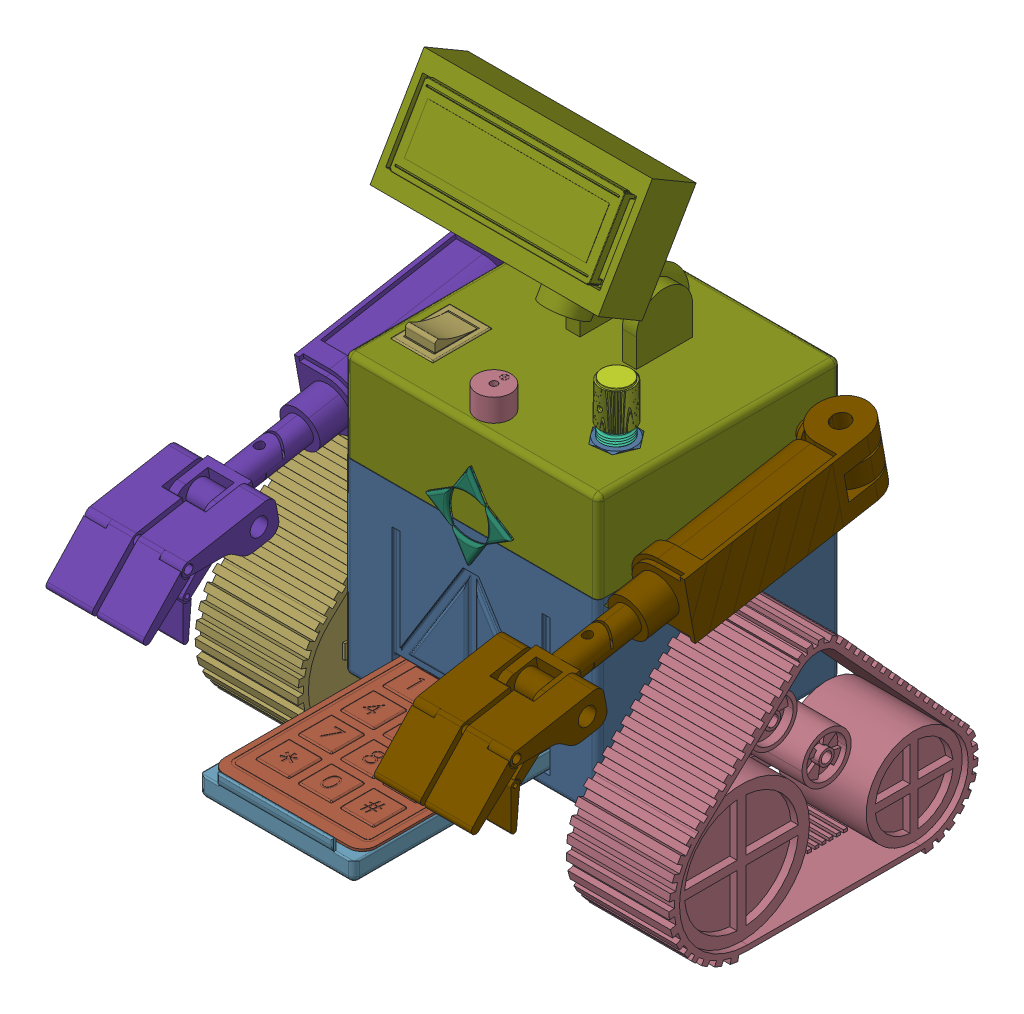
SolidWorks assembly Full Body with arms and wheels, configuration Default. Lengths in mm.
Overall size (168.14 212.39 174.48).
196 component instances, 67 part files, 27 mates.
Components (placement in the parent):
- Clock PCB.step-1: Clock PCB.step [Default] at (-3.837 -6.133 58.5856) size (81.95 80 25.5)
  - Board.step-1: Board.step [Default] at origin size (80 80 0.41)
    - Open CASCADE STEP translator 6.8 1.1.1.step-1: Open CASCADE STEP translator 6.8 1.1.1.step [Default] at (0 0 -0.4115) size (80 80 0.41)
  - XTAL1.step-1: XTAL1.step [Default] at origin size (11.36 4.66 3.61)
    - 6606830048.step-1: 6606830048.step [Default] at (28.0499 41.0499 0) size (11.36 4.66 1.01)
      - Extruded.step-1: Extruded.step [Default] at origin size (11.36 4.66 1.01)
    - 6606829968.step-1: 6606829968.step [Default] at (28.0499 41.0501 1) size (10.05 3.71 2.61)
      - Extruded-0.step-1: Extruded-0.step [Default] at origin size (10.05 3.71 2.61)
  - U2.step-1: U2.step [Default] at origin size (10.5 4.7 16.2)
    - 6606829888.step-1: 6606829888.step [Default] at (7.95 27.55 13.05) size (10.4 1.3 6.65)
      - Extruded-1.step-1: Extruded-1.step [Default] at origin size (10.4 1.3 6.65)
    - 6606829728.step-1: 6606829728.step [Default] at (7.95 25.9 3.5) size (10.5 4.7 9.55)
      - Extruded-2.step-1: Extruded-2.step [Default] at origin size (10.5 4.7 9.55)
  - U1.step-1: U1.step [Default] at origin size (63.7 16.03 14.45)
    - User_Library-ZIF-Socket-28-pin.step-1: User_Library-ZIF-Socket-28-pin.step [Default] at (43.5 28.05 0) x (1 0 0) z (0 0 1) size (63.7 16.03 14.45)
      - Contacts.step-1: Contacts.step [Default] at origin size (34.37 11.24 1.5)
      - Pins001.step-1: Pins001.step [Default] at origin size (33.87 8.47 3)
      - Screw002.step-1: Screw002.step [Default] at origin size (2.8 2.8 2)
      - Bottom-Shape.step-1: Bottom-Shape.step [Default] at origin size (50.4 15.02 8.11)
      - Lever-Tip.step-1: Lever-Tip.step [Default] at origin size (7 4.8 4.8)
      - Top-Shape.step-1: Top-Shape.step [Default] at origin size (50.4 15.02 3.8)
      - Push-Bar.step-1: Push-Bar.step [Default] at origin size (3.85 15.02 3.7)
      - Lever-Bar.step-1: Lever-Bar.step [Default] at origin size (19.2 11.43 1.62)
      - Screw001.step-1: Screw001.step [Default] at origin size (2.8 2.8 2)
  - Q1.step-1: Q1.step [Default] at origin size (3.05 4.08 12.8)
    - BC547-B.step-1: BC547-B.step [Default] at (72 53.1536 7) x (0 1 0) z (0 0 -1) size (4.08 3.05 12.8)
  - P3.step-1: P3.step [Default] at origin size (2.54 10.16 11.54)
    - 61300411121.step-1: 61300411121.step [Default] at (76.2999 22.6001 1.3) x (0 1 0) z (1 0 0) size (10.16 11.54 2.54)
      - 6130xx11121_PIN.step-1: 6130xx11121_PIN.step [Default] at (-3.81 1.5 0) x (1 0 0) z (0 -1 0) size (0.64 0.64 11.54)
      - 6130xx11121_PIN.step-2: 6130xx11121_PIN.step [Default] at (-1.27 1.5 0) x (1 0 0) z (0 -1 0) size (0.64 0.64 11.54)
      - 6130xx11121_PIN.step-3: 6130xx11121_PIN.step [Default] at (1.27 1.5 0) x (1 0 0) z (0 -1 0) size (0.64 0.64 11.54)
      - 6130xx11121_PIN.step-4: 6130xx11121_PIN.step [Default] at (3.81 1.5 0) x (1 0 0) z (0 -1 0) size (0.64 0.64 11.54)
      - 61300411121-3.step-1: 61300411121-3.step [Default] at origin size (10.16 2.54 2.54)
  - P2.step-1: P2.step [Default] at origin size (17.78 2.54 11.54)
    - 61300711121.step-1: 61300711121.step [Default] at (39.9599 3.8999 1.3) x (-1 0 0) z (0 1 0) size (17.78 11.54 2.54)
      - 6130xx11121_PIN-4.step-1: 6130xx11121_PIN-4.step [Default] at (-7.62 1.5 0) x (1 0 0) z (0 -1 0) size (0.64 0.64 11.54)
      - 6130xx11121_PIN-4.step-2: 6130xx11121_PIN-4.step [Default] at (-5.08 1.5 0) x (1 0 0) z (0 -1 0) size (0.64 0.64 11.54)
      - 6130xx11121_PIN-4.step-3: 6130xx11121_PIN-4.step [Default] at (-2.54 1.5 0) x (1 0 0) z (0 -1 0) size (0.64 0.64 11.54)
      - 6130xx11121_PIN-4.step-4: 6130xx11121_PIN-4.step [Default] at (0 1.5 0) x (1 0 0) z (0 -1 0) size (0.64 0.64 11.54)
      - 6130xx11121_PIN-4.step-5: 6130xx11121_PIN-4.step [Default] at (2.54 1.5 0) x (1 0 0) z (0 -1 0) size (0.64 0.64 11.54)
      - 6130xx11121_PIN-4.step-6: 6130xx11121_PIN-4.step [Default] at (5.08 1.5 0) x (1 0 0) z (0 -1 0) size (0.64 0.64 11.54)
      - 6130xx11121_PIN-4.step-7: 6130xx11121_PIN-4.step [Default] at (7.62 1.5 0) x (1 0 0) z (0 -1 0) size (0.64 0.64 11.54)
      - 61300711121-5.step-1: 61300711121-5.step [Default] at origin size (17.78 2.54 2.54)
  - P1.step-1: P1.step [Default] at origin size (30.48 2.54 11.54)
    - 61301211121.step-1: 61301211121.step [Default] at (41.3799 75.6999 1.3) x (-1 0 0) z (0 1 0) size (30.48 11.54 2.54)
      - 6130xx11121_PIN-6.step-1: 6130xx11121_PIN-6.step [Default] at (-13.97 1.5 0) x (1 0 0) z (0 -1 0) size (0.64 0.64 11.54)
      - 6130xx11121_PIN-6.step-2: 6130xx11121_PIN-6.step [Default] at (-11.43 1.5 0) x (1 0 0) z (0 -1 0) size (0.64 0.64 11.54)
      - 6130xx11121_PIN-6.step-3: 6130xx11121_PIN-6.step [Default] at (-8.89 1.5 0) x (1 0 0) z (0 -1 0) size (0.64 0.64 11.54)
      - 6130xx11121_PIN-6.step-4: 6130xx11121_PIN-6.step [Default] at (-6.35 1.5 0) x (1 0 0) z (0 -1 0) size (0.64 0.64 11.54)
      - 6130xx11121_PIN-6.step-5: 6130xx11121_PIN-6.step [Default] at (-3.81 1.5 0) x (1 0 0) z (0 -1 0) size (0.64 0.64 11.54)
      - 6130xx11121_PIN-6.step-6: 6130xx11121_PIN-6.step [Default] at (-1.27 1.5 0) x (1 0 0) z (0 -1 0) size (0.64 0.64 11.54)
      - 6130xx11121_PIN-6.step-7: 6130xx11121_PIN-6.step [Default] at (1.27 1.5 0) x (1 0 0) z (0 -1 0) size (0.64 0.64 11.54)
      - 6130xx11121_PIN-6.step-8: 6130xx11121_PIN-6.step [Default] at (3.81 1.5 0) x (1 0 0) z (0 -1 0) size (0.64 0.64 11.54)
      - 6130xx11121_PIN-6.step-9: 6130xx11121_PIN-6.step [Default] at (6.35 1.5 0) x (1 0 0) z (0 -1 0) size (0.64 0.64 11.54)
      - 6130xx11121_PIN-6.step-10: 6130xx11121_PIN-6.step [Default] at (8.89 1.5 0) x (1 0 0) z (0 -1 0) size (0.64 0.64 11.54)
      - 6130xx11121_PIN-6.step-11: 6130xx11121_PIN-6.step [Default] at (11.43 1.5 0) x (1 0 0) z (0 -1 0) size (0.64 0.64 11.54)
      - 6130xx11121_PIN-6.step-12: 6130xx11121_PIN-6.step [Default] at (13.97 1.5 0) x (1 0 0) z (0 -1 0) size (0.64 0.64 11.54)
      - 61301211121-7.step-1: 61301211121-7.step [Default] at origin size (30.48 2.54 2.54)
  - KEY5.step-1: KEY5.step [Default] at origin size (7.8 5.99 8.11)
    - Switch_TE_1825910-2_eec.step-1: Switch_TE_1825910-2_eec.step [Default] at (68.1 13.85 0) size (7.8 5.99 8.11)
      - Body.step-1: Body.step [Default] at (0 0 4.3) x (0 -1 0) z (0 0 1) size (5.99 5.99 3.9)
      - button.step-1: button.step [Default] at (0 0 4.3) x (0 -1 0) z (0 0 1) size (3.51 3.51 1.1)
      - cover.step-1: cover.step [Default] at (0 0 4.3) x (0 -1 0) z (0 0 1) size (5.99 5.99 0.1)
      - leads.step-1: leads.step [Default] at (0 0 4.3) x (0 -1 0) z (0 0 1) size (5.21 7.8 4.81)
      - circle.step-1: circle.step [Default] at (-2.6803 2.6863 3.6) size (0.4 0.4 0)
      - TE_Connectivity.step-1: TE_Connectivity.step [Default] at (-0.1925 -2.4218 3.6) size (2.27 0.85 0.01)
  - KEY4.step-1: KEY4.step [Default] at origin size (7.8 5.99 8.11)
    - Switch_TE_1825910-2_eec.step-1: Switch_TE_1825910-2_eec.step [Default] at (50 55 0) size (7.8 5.99 8.11)
      - Body.step-1: Body.step [Default] at (0 0 4.3) x (0 -1 0) z (0 0 1) size (5.99 5.99 3.9)
      - button.step-1: button.step [Default] at (0 0 4.3) x (0 -1 0) z (0 0 1) size (3.51 3.51 1.1)
      - cover.step-1: cover.step [Default] at (0 0 4.3) x (0 -1 0) z (0 0 1) size (5.99 5.99 0.1)
      - leads.step-1: leads.step [Default] at (0 0 4.3) x (0 -1 0) z (0 0 1) size (5.21 7.8 4.81)
      - circle.step-1: circle.step [Default] at (-2.6803 2.6863 3.6) size (0.4 0.4 0)
      - TE_Connectivity.step-1: TE_Connectivity.step [Default] at (-0.1925 -2.4218 3.6) size (2.27 0.85 0.01)
  - KEY3.step-1: KEY3.step [Default] at origin size (7.8 5.99 8.11)
    - Switch_TE_1825910-2_eec.step-1: Switch_TE_1825910-2_eec.step [Default] at (30 55 0) size (7.8 5.99 8.11)
      - Body.step-1: Body.step [Default] at (0 0 4.3) x (0 -1 0) z (0 0 1) size (5.99 5.99 3.9)
      - button.step-1: button.step [Default] at (0 0 4.3) x (0 -1 0) z (0 0 1) size (3.51 3.51 1.1)
      - cover.step-1: cover.step [Default] at (0 0 4.3) x (0 -1 0) z (0 0 1) size (5.99 5.99 0.1)
      - leads.step-1: leads.step [Default] at (0 0 4.3) x (0 -1 0) z (0 0 1) size (5.21 7.8 4.81)
      - circle.step-1: circle.step [Default] at (-2.6803 2.6863 3.6) size (0.4 0.4 0)
      - TE_Connectivity.step-1: TE_Connectivity.step [Default] at (-0.1925 -2.4218 3.6) size (2.27 0.85 0.01)
  - KEY2.step-1: KEY2.step [Default] at origin size (7.8 5.99 8.11)
    - Switch_TE_1825910-2_eec.step-1: Switch_TE_1825910-2_eec.step [Default] at (40 45 0) size (7.8 5.99 8.11)
      - Body.step-1: Body.step [Default] at (0 0 4.3) x (0 -1 0) z (0 0 1) size (5.99 5.99 3.9)
      - button.step-1: button.step [Default] at (0 0 4.3) x (0 -1 0) z (0 0 1) size (3.51 3.51 1.1)
      - cover.step-1: cover.step [Default] at (0 0 4.3) x (0 -1 0) z (0 0 1) size (5.99 5.99 0.1)
      - leads.step-1: leads.step [Default] at (0 0 4.3) x (0 -1 0) z (0 0 1) size (5.21 7.8 4.81)
      - circle.step-1: circle.step [Default] at (-2.6803 2.6863 3.6) size (0.4 0.4 0)
      - TE_Connectivity.step-1: TE_Connectivity.step [Default] at (-0.1925 -2.4218 3.6) size (2.27 0.85 0.01)
  - KEY1.step-1: KEY1.step [Default] at origin size (7.8 5.99 8.11)
    - Switch_TE_1825910-2_eec.step-1: Switch_TE_1825910-2_eec.step [Default] at (40 65 0) size (7.8 5.99 8.11)
      - Body.step-1: Body.step [Default] at (0 0 4.3) x (0 -1 0) z (0 0 1) size (5.99 5.99 3.9)
      - button.step-1: button.step [Default] at (0 0 4.3) x (0 -1 0) z (0 0 1) size (3.51 3.51 1.1)
      - cover.step-1: cover.step [Default] at (0 0 4.3) x (0 -1 0) z (0 0 1) size (5.99 5.99 0.1)
      - leads.step-1: leads.step [Default] at (0 0 4.3) x (0 -1 0) z (0 0 1) size (5.21 7.8 4.81)
      - circle.step-1: circle.step [Default] at (-2.6803 2.6863 3.6) size (0.4 0.4 0)
      - TE_Connectivity.step-1: TE_Connectivity.step [Default] at (-0.1925 -2.4218 3.6) size (2.27 0.85 0.01)
  - JST2.step-1: JST2.step [Default] at origin size (4.7 6 10.05)
    - Conn_TE_Connectivity_440054-2_eec.step-1: Conn_TE_Connectivity_440054-2_eec.step [Default] at (72.85 68.85 0) x (0 -1 0) z (0 0 1) size (6 4.7 10.05)
      - 1.step-1: 1.step [Default] at (0 -0.6 6.05) size (2.5 2.35 8.8)
      - 2.step-1: 2.step [Default] at (0 -0.6 6.05) size (0.9 0.1 1.08)
      - 3.step-1: 3.step [Default] at (0 -0.6 6.05) size (6 4.7 6.35)
      - TE_connectivity_Logo_1_(2).step-1: TE_connectivity_Logo_1_(2).step [Default] at (2.901 6.9182 0.6322) x (0 -1 0) z (1 0 0) size (1.49 0.53 0.1)
  - JST1.step-1: JST1.step [Default] at origin size (6 4.7 10.05)
    - Conn_TE_Connectivity_440054-2_eec.step-1: Conn_TE_Connectivity_440054-2_eec.step [Default] at (10.55 4.25 0) x (-1 0 0) z (0 0 1) size (6 4.7 10.05)
      - 1.step-1: 1.step [Default] at (0 -0.6 6.05) size (2.5 2.35 8.8)
      - 2.step-1: 2.step [Default] at (0 -0.6 6.05) size (0.9 0.1 1.08)
      - 3.step-1: 3.step [Default] at (0 -0.6 6.05) size (6 4.7 6.35)
      - TE_connectivity_Logo_1_(2).step-1: TE_connectivity_Logo_1_(2).step [Default] at (2.901 6.9182 0.6322) x (0 -1 0) z (1 0 0) size (1.49 0.53 0.1)
  - JST3.step-1: JST3.step [Default] at origin size (7.9 4.5 9.4)
    - 6606829248.step-1: 6606829248.step [Default] at (11.9 70.55 -3.4) size (0.5 0.5 8.45)
      - Extruded-8.step-1: Extruded-8.step [Default] at origin size (0.5 0.5 8.45)
    - 6606829248.step-2: 6606829248.step [Default] at (7.9 70.55 -3.4) size (0.5 0.5 8.45)
      - Extruded-8.step-1: Extruded-8.step [Default] at origin size (0.5 0.5 8.45)
    - 6606829248.step-3: 6606829248.step [Default] at (9.9 70.55 -3.4) size (0.5 0.5 8.45)
      - Extruded-8.step-1: Extruded-8.step [Default] at origin size (0.5 0.5 8.45)
    - 6606828928.step-1: 6606828928.step [Default] at (9.9 70.2 0) size (6.6 4.1 1.75)
      - Extruded-9.step-1: Extruded-9.step [Default] at origin size (6.6 4.1 1.75)
    - 6606828768.step-1: 6606828768.step [Default] at (9.9 68.875 0) size (7.9 2.25 6)
      - Extruded-10.step-1: Extruded-10.step [Default] at origin size (7.9 2.25 6)
    - 6606828608.step-1: 6606828608.step [Default] at (7.525 71.525 0) size (3.15 1.45 6)
      - Extruded-11.step-1: Extruded-11.step [Default] at origin size (3.15 1.45 6)
    - 6606828448.step-1: 6606828448.step [Default] at (6.275 70.4 0) size (0.65 0.8 4.1)
      - Extruded-12.step-1: Extruded-12.step [Default] at origin size (0.65 0.8 4.1)
    - 6606828448.step-2: 6606828448.step [Default] at (13.525 70.4 0) size (0.65 0.8 4.1)
      - Extruded-12.step-1: Extruded-12.step [Default] at origin size (0.65 0.8 4.1)
    - 6606828208.step-1: 6606828208.step [Default] at (12.275 71.525 0) size (3.15 1.45 6)
      - Extruded-13.step-1: Extruded-13.step [Default] at origin size (3.15 1.45 6)
  - C6.step-1: C6.step [Default] at origin size (8 8 14.5)
    - Aluminum_electrolytic_capacitor_radial_D8_H11.5_PinD0.6_Pitch3.5_nominal_black.step-1: Aluminum_electrolytic_capacitor_radial_D8_H11.5_PinD0.6_Pitch3.5_nominal_black.step [Default] at (64.35 73.55 0) x (-1 0 0) z (0 0 1) size (1.1 2.07 11.1)
    - Aluminum_electrolytic_capacitor_radial_D8_H11.5_PinD0.6_Pitch3.5_nominal_black-14.step-1: Aluminum_electrolytic_capacitor_radial_D8_H11.5_PinD0.6_Pitch3.5_nominal_black-14.step [Default] at (64.35 73.55 0) x (-1 0 0) z (0 0 1) size (7.86 8 11.1)
    - Aluminum_electrolytic_capacitor_radial_D8_H11.5_PinD0.6_Pitch3.5_nominal_black-15.step-1: Aluminum_electrolytic_capacitor_radial_D8_H11.5_PinD0.6_Pitch3.5_nominal_black-15.step [Default] at (64.35 73.55 0) x (-1 0 0) z (0 0 1) size (7.8 7.8 10.9)
    - Aluminum_electrolytic_capacitor_radial_D8_H11.5_PinD0.6_Pitch3.5_nominal_black-16.step-1: Aluminum_electrolytic_capacitor_radial_D8_H11.5_PinD0.6_Pitch3.5_nominal_black-16.step [Default] at (64.35 73.55 0) x (-1 0 0) z (0 0 1) size (7.4 7.4 1.6)
    - Aluminum_electrolytic_capacitor_radial_D8_H11.5_PinD0.6_Pitch3.5_nominal_black-17.step-1: Aluminum_electrolytic_capacitor_radial_D8_H11.5_PinD0.6_Pitch3.5_nominal_black-17.step [Default] at (64.35 73.55 0) x (-1 0 0) z (0 0 1) size (4.1 0.6 3)
  - C5.step-1: C5.step [Default] at origin size (8 8 14.5)
    - Aluminum_electrolytic_capacitor_radial_D8_H11.5_PinD0.6_Pitch3.5_nominal_black.step-1: Aluminum_electrolytic_capacitor_radial_D8_H11.5_PinD0.6_Pitch3.5_nominal_black.step [Default] at (65.05 5.25 0) size (1.1 2.07 11.1)
    - Aluminum_electrolytic_capacitor_radial_D8_H11.5_PinD0.6_Pitch3.5_nominal_black-14.step-1: Aluminum_electrolytic_capacitor_radial_D8_H11.5_PinD0.6_Pitch3.5_nominal_black-14.step [Default] at (65.05 5.25 0) size (7.86 8 11.1)
    - Aluminum_electrolytic_capacitor_radial_D8_H11.5_PinD0.6_Pitch3.5_nominal_black-15.step-1: Aluminum_electrolytic_capacitor_radial_D8_H11.5_PinD0.6_Pitch3.5_nominal_black-15.step [Default] at (65.05 5.25 0) size (7.8 7.8 10.9)
    - Aluminum_electrolytic_capacitor_radial_D8_H11.5_PinD0.6_Pitch3.5_nominal_black-16.step-1: Aluminum_electrolytic_capacitor_radial_D8_H11.5_PinD0.6_Pitch3.5_nominal_black-16.step [Default] at (65.05 5.25 0) size (7.4 7.4 1.6)
    - Aluminum_electrolytic_capacitor_radial_D8_H11.5_PinD0.6_Pitch3.5_nominal_black-17.step-1: Aluminum_electrolytic_capacitor_radial_D8_H11.5_PinD0.6_Pitch3.5_nominal_black-17.step [Default] at (65.05 5.25 0) size (4.1 0.6 3)
  - C4.step-1: C4.step [Default] at origin size (5.99 5.99 8.89)
    - Cap_Murata_RCE5C2A3R0C0K1H03B_eec.step-1: Cap_Murata_RCE5C2A3R0C0K1H03B_eec.step [Default] at (13.7 39.4 0) x (1 0 0) z (0 0 1) size (5.99 5.99 8.89)
      - Body.step-1: Body.step [Default] at origin size (5.99 5.99 3.9)
      - leads-18.step-1: leads-18.step [Default] at origin size (5.5 0.5 6.65)
      - logo.step-1: logo.step [Default] at (0 -1.25 8.5) x (1 0 0) z (0 -1 0) size (1.98 0.46 0.01)
  - C3.step-1: C3.step [Default] at origin size (5.99 5.99 8.89)
    - Cap_Murata_RCE5C2A3R0C0K1H03B_eec.step-1: Cap_Murata_RCE5C2A3R0C0K1H03B_eec.step [Default] at (13.65 43.7 0) x (1 0 0) z (0 0 1) size (5.99 5.99 8.89)
      - Body.step-1: Body.step [Default] at origin size (5.99 5.99 3.9)
      - leads-18.step-1: leads-18.step [Default] at origin size (5.5 0.5 6.65)
      - logo.step-1: logo.step [Default] at (0 -1.25 8.5) x (1 0 0) z (0 -1 0) size (1.98 0.46 0.01)
  - C2.step-1: C2.step [Default] at origin size (8 8 14.5)
    - Aluminum_electrolytic_capacitor_radial_D8_H11.5_PinD0.6_Pitch3.5_nominal_black.step-1: Aluminum_electrolytic_capacitor_radial_D8_H11.5_PinD0.6_Pitch3.5_nominal_black.step [Default] at (17.55 14.1 0) size (1.1 2.07 11.1)
    - Aluminum_electrolytic_capacitor_radial_D8_H11.5_PinD0.6_Pitch3.5_nominal_black-14.step-1: Aluminum_electrolytic_capacitor_radial_D8_H11.5_PinD0.6_Pitch3.5_nominal_black-14.step [Default] at (17.55 14.1 0) size (7.86 8 11.1)
    - Aluminum_electrolytic_capacitor_radial_D8_H11.5_PinD0.6_Pitch3.5_nominal_black-15.step-1: Aluminum_electrolytic_capacitor_radial_D8_H11.5_PinD0.6_Pitch3.5_nominal_black-15.step [Default] at (17.55 14.1 0) size (7.8 7.8 10.9)
    - Aluminum_electrolytic_capacitor_radial_D8_H11.5_PinD0.6_Pitch3.5_nominal_black-16.step-1: Aluminum_electrolytic_capacitor_radial_D8_H11.5_PinD0.6_Pitch3.5_nominal_black-16.step [Default] at (17.55 14.1 0) size (7.4 7.4 1.6)
    - Aluminum_electrolytic_capacitor_radial_D8_H11.5_PinD0.6_Pitch3.5_nominal_black-17.step-1: Aluminum_electrolytic_capacitor_radial_D8_H11.5_PinD0.6_Pitch3.5_nominal_black-17.step [Default] at (17.55 14.1 0) size (4.1 0.6 3)
  - C1.step-1: C1.step [Default] at origin size (8 8 14.5)
    - Aluminum_electrolytic_capacitor_radial_D8_H11.5_PinD0.6_Pitch3.5_nominal_black.step-1: Aluminum_electrolytic_capacitor_radial_D8_H11.5_PinD0.6_Pitch3.5_nominal_black.step [Default] at (7.05 14.5 0) size (1.1 2.07 11.1)
    - Aluminum_electrolytic_capacitor_radial_D8_H11.5_PinD0.6_Pitch3.5_nominal_black-14.step-1: Aluminum_electrolytic_capacitor_radial_D8_H11.5_PinD0.6_Pitch3.5_nominal_black-14.step [Default] at (7.05 14.5 0) size (7.86 8 11.1)
    - Aluminum_electrolytic_capacitor_radial_D8_H11.5_PinD0.6_Pitch3.5_nominal_black-15.step-1: Aluminum_electrolytic_capacitor_radial_D8_H11.5_PinD0.6_Pitch3.5_nominal_black-15.step [Default] at (7.05 14.5 0) size (7.8 7.8 10.9)
    - Aluminum_electrolytic_capacitor_radial_D8_H11.5_PinD0.6_Pitch3.5_nominal_black-16.step-1: Aluminum_electrolytic_capacitor_radial_D8_H11.5_PinD0.6_Pitch3.5_nominal_black-16.step [Default] at (7.05 14.5 0) size (7.4 7.4 1.6)
    - Aluminum_electrolytic_capacitor_radial_D8_H11.5_PinD0.6_Pitch3.5_nominal_black-17.step-1: Aluminum_electrolytic_capacitor_radial_D8_H11.5_PinD0.6_Pitch3.5_nominal_black-17.step [Default] at (7.05 14.5 0) size (4.1 0.6 3)
  - Free-Models.step-1: Free-Models.step [Default] at origin size (34.6 9.68 7.3)
    - atmega328p-pu.step-1: atmega328p-pu.step [Default] at (59.217 28 11) x (-1 0 0) z (0 1 0) size (34.6 7.3 9.68)
- Part46^Full Body with arms and wheels-1: Part46^Full Body with arms and wheels [Default] at origin size (90 95.83 86) (virtual)
- Matrix Keypad 12 Key (4X3)-3: Matrix Keypad 12 Key (4X3) [Default] at (35.713 -10.233 128.1202) x (1 0 0) z (0 1 0) size (54 77 1.31)
- wheel 2-2: wheel 2 [Default] at (-18.6112 -22.8736 33.5298) size (56.04 84.58 109.67)
- Mirrorwheel 2-5: Mirrorwheel 2 [Default] at (91.0372 -22.8736 33.5298) x (-1 0 0) z (0 0 -1) size (56.04 84.58 109.67)
- Part4^Full Body with arms and wheels-1: Part4^Full Body with arms and wheels [Default] at (35.713 -10.233 128.1202) x (-1 0 0) z (0 -1 0) size (55 82.09 11) (virtual)
- Part5-1: Part5 [Default] at (0 0 101.5856) size (12.45 10.37 39.83)
- upper part-1: upper part [Default] at (71.8557 119.3769 -12.5727) x (-1 0 0) z (0 0 1) size (92 118.62 86)
- Right Side Arm-1: Right Side Arm [Default] at (-22.5115 49.6226 93.099) x (0 -0.177317 0.984154) z (1 0 0) size (161.81 40.01 34.94)
- MirrorRight Side Arm-2: MirrorRight Side Arm [Default] at (94.9376 49.6226 93.099) x (0 -0.177317 0.984154) z (1 0 0) size (161.81 40.01 34.94)
- Part5-2: Part5 [Default] at (72.326 97.7339 101.5999) x (-1 0 0) z (0 0 1) size (12.45 10.37 39.83)
- Part5-3: Part5 [Default] at (85.03 12.7039 101.5837) x (0 1 0) z (0 0 1) size (12.45 10.37 39.83)
- Part5-4: Part5 [Default] at (-12.7039 85.03 101.5758) x (0 -1 0) z (0 0 1) size (12.45 10.37 39.83)
- BATTARY HOLDER-1: BATTARY HOLDER [По умолчанию] at (35.2784 56.667 45.2722) x (1 0 0) z (0 1 0) size (54.61 19.5 29.97)
- 100 ohm Sigle Potentiometer Assembly.STEP-2: 100 ohm Sigle Potentiometer Assembly.STEP [Default] at (63.4133 58.8792 87.7867) x (-1 0 0) z (0 -1 0) size (25.4 26.22 29.59)
  - Body.step-1: Body.step [Default] at (-2.7005 7.9259 -10.2577) size (5.99 5.99 3.9)
  - PCB.STEP-1: PCB.STEP [Default] at (-2.7005 7.9259 -11.5277) size (16.64 19.94 1.27)
  - Plate.STEP-1: Plate.STEP [Default] at (-2.7005 7.9259 -12.1627) size (17.02 10.92 0.64)
  - Wire_Tab.STEP-1: Wire_Tab.STEP [Default] at (-5.8755 14.4664 -10.2577) x (0 1 0) z (0 0 1) size (6.98 3.81 4.44)
  - Wire_Tab.STEP-2: Wire_Tab.STEP [Default] at (-0.7955 14.4664 -10.2577) x (0 1 0) z (0 0 1) size (6.98 3.81 4.44)
  - Wire_Tab.STEP-3: Wire_Tab.STEP [Default] at (4.2845 14.4664 -10.2577) x (0 1 0) z (0 0 1) size (6.98 3.81 4.44)
  - Rivet.STEP-1: Rivet.STEP [Default] at (-7.7805 16.3714 -9.6227) x (-0.923728 -0.383049 0) z (0 0 -1) size (2.54 3.49 2.22)
  - Rivet.STEP-2: Rivet.STEP [Default] at (-2.7005 16.3714 -9.6227) x (-0.923728 -0.383049 0) z (0 0 -1) size (2.54 3.49 2.22)
  - Rivet.STEP-3: Rivet.STEP [Default] at (2.3795 16.3714 -9.6227) x (-0.923728 -0.383049 0) z (0 0 -1) size (2.54 3.49 2.22)
  - Barrell2.STEP-1: Barrell2.STEP [Default] at (-2.7005 7.9259 -21.6877) size (10.47 10.4 9.53)
  - Potentiometer Knob.STEP-1: Potentiometer Knob.STEP [Default] at (-10.5959 -2.0877 -35.9117) x (-1 0 0) z (0 0 -1) size (11.86 13.59 13.46)
  - Shaft.STEP-1: Shaft.STEP [Default] at (-2.7005 7.9259 -14.3217) x (-0.923728 -0.383049 0) z (0 0 -1) size (5.97 5.97 23.75)
  - Washer^100 ohm Sigle Potentiometer Assembly.STEP-1: Washer^100 ohm Sigle Potentiometer Assembly.STEP [Default] at (-2.7005 7.9259 -13.4327) x (-1 0 0) z (0 0 -1) size (14.25 14.25 0.89)
  - hex nut jam_am_B18.2.4.5M - Hex jam nut,  M8 x 1.25 --D-N.STEP-1: hex nut jam_am_B18.2.4.5M - Hex jam nut,  M8 x 1.25 --D-N.STEP [Default] at (-2.7005 7.9259 -18.3217) x (0.923728 0.383049 0) z (0 0 -1) size (15.02 15.02 4.01)
  - Level Indicator Plate^100 ohm Sigle Potentiometer Assembly.STEP-1: Level Indicator Plate^100 ohm Sigle Potentiometer Assembly.STEP [Default] at (-2.7005 7.9259 -12.1627) x (-1 0 0) z (0 0 -1) size (25.4 25.4 1.27)
- 64_Switch.step-3: 64_Switch.step [Default] at (-4.4212 65.1862 87.4502) x (0 0 -1) z (1 0 0) size (23 26.97 15)
- TMB12A05.step-5: TMB12A05.step [Default] at (35.6935 75.257 96.7253) x (1 0 0) z (0 1 0) size (12 12 11.85)
Mates (geometry in assembly coordinates):
- Perpendicular1: perpendicular: plane of Part46^Full Body with arms and wheels-1 through (-8.787 -22.233 101.5856) normal (0 -1 0); plane of wheel 2-2 through (-10.3877 -22.301 50.7401) normal (0 0 -1)
- InPlace1: in place: plane of ? through (70.3473 -28.3571 185.2121) normal (0 -1 0); plane of ? through (0 -28.3571 0) normal (0 -1 0); moOrthogonalPlaneRef_w of ? through (70.3473 -28.3571 185.2121) normal (0 -1 0); plane of ? through (0 -28.3571 0) normal (0 0 -1); plane of ? through (70.3473 -28.3571 185.2121) normal (0 -1 0); plane of ? through (0 -28.3571 0) normal (-1 0 0); plane of Matrix Keypad 12 Key (4X3)-3 through (35.713 -10.233 128.1202) normal (0 -1 0); unknown of Part4^Full Body with arms and wheels-1
- Coincident8: coincident aligned: plane of Matrix Keypad 12 Key (4X3)-3; plane of Part4^Full Body with arms and wheels-1
- Coincident9: coincident aligned: moOrthogonalPlaneRef_w of Matrix Keypad 12 Key (4X3)-3 through (35.713 -10.233 128.1202) normal (0 0 -1); plane of Part4^Full Body with arms and wheels-1 through (35.713 -10.233 128.1202) normal (0 0 -1)
- Coincident10: coincident anti-aligned: moOrthogonalPlaneRef_w of Matrix Keypad 12 Key (4X3)-3 through (35.713 -10.233 128.1202) normal (1 0 0); plane of Part4^Full Body with arms and wheels-1 through (35.713 -10.233 128.1202) normal (-1 0 0)
- Coincident9: coincident anti-aligned: plane of Part46^Full Body with arms and wheels-1 through (8.213 -6.233 21.5856) normal (1 0 0); plane of Part4^Full Body with arms and wheels-1 through (8.213 -17.233 170.0772) normal (-1 0 0)
- Parallel3: parallel anti-aligned: plane of Part46^Full Body with arms and wheels-1 through (64.213 -6.233 21.5856) normal (-1 0 0); plane of Part4^Full Body with arms and wheels-1 through (63.213 -17.233 170.0772) normal (1 0 0)
- InPlace2: in place: plane of Part46^Full Body with arms and wheels-1 through (0 0 101.5856) normal (0 0 1); plane of Part5-1 through (0 0 101.5856) normal (0 0 1); plane of Part46^Full Body with arms and wheels-1 through (0 0 101.5856) normal (0 0 1); plane of Part5-1 through (0 0 101.5856) normal (0 1 0); plane of Part46^Full Body with arms and wheels-1 through (0 0 101.5856) normal (0 0 1); plane of Part5-1 through (0 0 101.5856) normal (1 0 0); plane of Part46^Full Body with arms and wheels-1 through (0 0 101.5856) normal (0 0 1); unknown of Part5-1
- Coincident14: coincident aligned: plane of Part46^Full Body with arms and wheels-1; plane of Part5-1
- Coincident15: coincident aligned: moOrthogonalPlaneRef_w of Part46^Full Body with arms and wheels-1 through (0 0 101.5856) normal (0 1 0); plane of Part5-1 through (0 0 101.5856) normal (0 1 0)
- Coincident16: coincident anti-aligned: moOrthogonalPlaneRef_w of Part46^Full Body with arms and wheels-1 through (0 0 101.5856) normal (-1 0 0); plane of Part5-1 through (0 0 101.5856) normal (1 0 0)
- Coincident1: coincident anti-aligned: plane of Part46^Full Body with arms and wheels-1 through (-8.787 44.767 101.5856) normal (0 1 0); plane of upper part-1 through (36.195 44.767 58.3799) normal (0 -1 0)
- Lock4: lock: unknown of Part46^Full Body with arms and wheels-1; unknown of upper part-1
- Lock5: lock: unknown of Part46^Full Body with arms and wheels-1; unknown of wheel 2-2
- Concentric4: concentric anti-aligned: cylinder of upper part-1 through (1.195 61.1485 28.2478) axis (-1 0 0) radius 3.0785; cylinder of Right Side Arm-1 through (-4.3231 61.1485 28.2478) axis (1 0 0) radius 3.062
- Lock6: lock: unknown of upper part-1; unknown of Right Side Arm-1
- Lock9: lock: unknown of upper part-1; unknown of Part5-4
- Coincident2: coincident anti-aligned: plane of Part46^Full Body with arms and wheels-1 through (79.213 -6.233 45.2722) normal (0 0 -1); plane of BATTARY HOLDER-1 through (35.2784 56.667 45.2722) normal (0 0 1)
- Lock10: lock: unknown of Part46^Full Body with arms and wheels-1; unknown of BATTARY HOLDER-1
- Coincident3: coincident anti-aligned: plane of upper part-1 through (-4.4892 66.767 89.4502) normal (0 0 -1); plane of 64_Switch.step-3 through (-3.9212 75.6862 89.4502) normal (0 0 1)
- Parallel4: parallel anti-aligned: plane of upper part-1 through (-4.4892 66.767 68.3789) normal (0 0 1); plane of 64_Switch.step-3 through (-3.9212 75.6862 68.4502) normal (0 0 -1)
- Parallel5: parallel anti-aligned: plane of upper part-1 through (-4.4892 66.767 68.3789) normal (1 0 0); plane of 64_Switch.step-3 through (-4.4212 75.6862 88.9502) normal (-1 0 0)
- Coincident5: coincident anti-aligned: plane of upper part-1 through (10.5788 66.767 68.3789) normal (-1 0 0); plane of 64_Switch.step-3 through (10.5788 75.6862 88.9502) normal (1 0 0)
- Lock11: lock: unknown of upper part-1; unknown of 64_Switch.step-3
- Concentric5: concentric anti-aligned: circle of upper part-1; cylinder of TMB12A05.step-5 through (35.6935 75.267 92.9353) axis (0 -1 0) radius 6
- Coincident7: coincident anti-aligned: plane of upper part-1 through (35.6935 75.267 92.9353) normal (0 1 0); plane of TMB12A05.step-5 through (35.6935 75.267 92.9353) normal (0 -1 0)
- Coincident8: coincident anti-aligned: plane of Part46^Full Body with arms and wheels-1 through (6.213 -17.233 21.5856) normal (0 1 0); plane of Part4^Full Body with arms and wheels-1 through (35.713 -17.233 128.1202) normal (0 -1 0)
